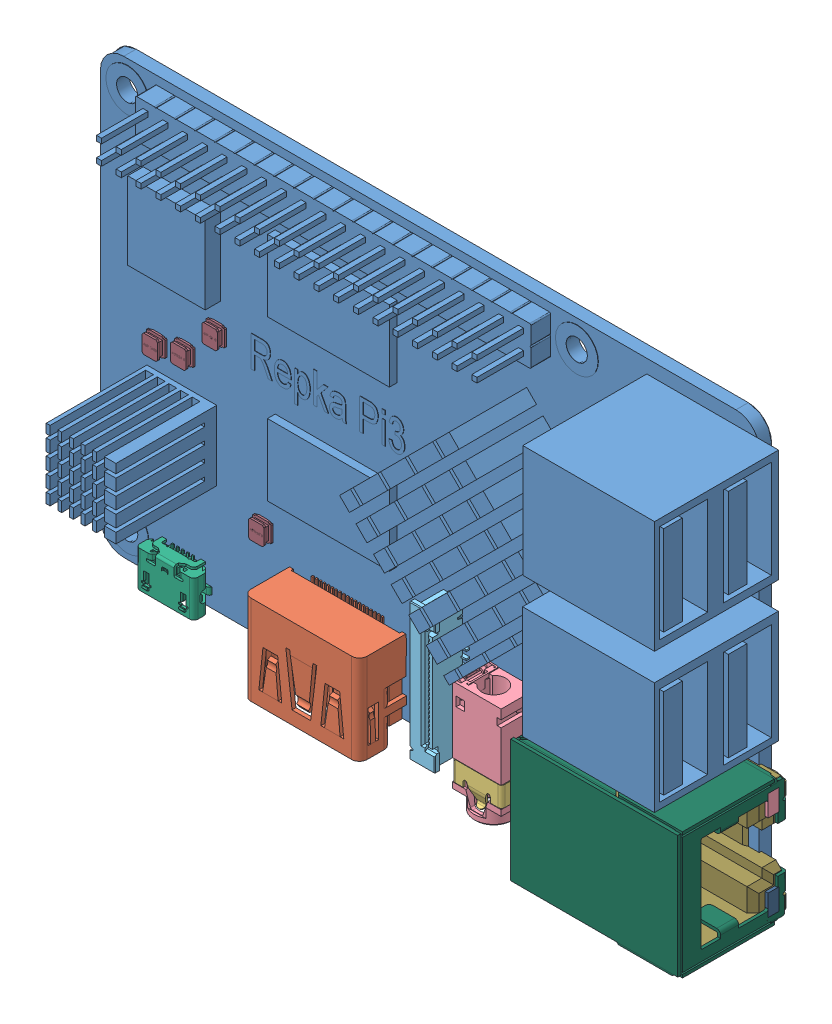
SolidWorks assembly Сборка RepkaPi3, configuration По умолчанию. Lengths in mm.
Overall size (90.06 58 20.41).
57 component instances, 49 part files, 29 mates.
Components (placement in the parent):
- Копия Repka Pi 3 (3D)^Сборка RepkaPi3-1: Копия Repka Pi 3 (3D)^Сборка RepkaPi3 [По умолчанию] at origin size (87.5 56 19.23) (virtual)
- Копия HDMI^Сборка RepkaPi3-1: Копия HDMI^Сборка RepkaPi3 [По умолчанию] at (-5.1944 -35.2371 4.905) x (1 0 0) z (0 -1 0) size (15 7.58 12) (virtual)
- Копия jack3.5_4pin^Сборка RepkaPi3-1: Копия jack3.5_4pin^Сборка RepkaPi3 [По умолчанию] at (-62.0064 -11.1249 -30.918) x (1 0 0) z (0 0 -1) size (8.31 14 5.4) (virtual)
  - Копия CUI_DEVICES_SJ2-35894D-SMT-TR_2^Копия jack3.5_4pin_Сборка RepkaPi3-1: Копия CUI_DEVICES_SJ2-35894D-SMT-TR_2^Копия jack3.5_4pin_Сборка RepkaPi3 [По умолчанию] at origin size (7.35 4.38 4.6) (virtual)
  - Копия CUI_DEVICES_SJ2-35894D-SMT-TR^Копия jack3.5_4pin_Сборка RepkaPi3-1: Копия CUI_DEVICES_SJ2-35894D-SMT-TR^Копия jack3.5_4pin_Сборка RepkaPi3 [По умолчанию] at origin size (8.31 14 5.4) (virtual)
- Копия Шимка^Сборка RepkaPi3-1: Копия Шимка^Сборка RepkaPi3 [По умолчанию] at (8.5556 -24.5871 5.05) x (0 1 0) z (0 0 1) size (17.7 3.8 4.15) (virtual)
- Копия МИКРО ЮСБ^Сборка RepkaPi3-1: Копия МИКРО ЮСБ^Сборка RepkaPi3 [Default] at (-26.4444 -31.2871 2.825) x (1 0 0) z (0 -1 0) size (8.21 3.3 5.5) (virtual)
- Копия ОБРАТНАЯ СТОРОНА^Сборка RepkaPi3-1: Копия ОБРАТНАЯ СТОРОНА^Сборка RepkaPi3 [По умолчанию] at (-28.8944 -3.2371 0) x (0 1 0) z (-1 0 0) size (16.11 2.45 17.8) (virtual)
  - Копия ST-TF-003A_8^Копия ОБРАТНАЯ СТОРОНА_Сборка RepkaPi3-1: Копия ST-TF-003A_8^Копия ОБРАТНАЯ СТОРОНА_Сборка RepkaPi3 [По умолчанию] at origin size (16.11 1.9 14.7) (virtual)
  - Копия ST-TF-003A_3^Копия ОБРАТНАЯ СТОРОНА_Сборка RepkaPi3-1: Копия ST-TF-003A_3^Копия ОБРАТНАЯ СТОРОНА_Сборка RepkaPi3 [По умолчанию] at origin size (1.15 1.16 8.91) (virtual)
  - Копия ST-TF-003A_2^Копия ОБРАТНАЯ СТОРОНА_Сборка RepkaPi3-1: Копия ST-TF-003A_2^Копия ОБРАТНАЯ СТОРОНА_Сборка RepkaPi3 [По умолчанию] at origin size (0.45 0.95 2.68) (virtual)
  - Копия ST-TF-003A^Копия ОБРАТНАЯ СТОРОНА_Сборка RepkaPi3-1: Копия ST-TF-003A^Копия ОБРАТНАЯ СТОРОНА_Сборка RepkaPi3 [По умолчанию] at origin size (0.78 0.5 4.38) (virtual)
  - Копия ST-TF-003A_11^Копия ОБРАТНАЯ СТОРОНА_Сборка RepkaPi3-1: Копия ST-TF-003A_11^Копия ОБРАТНАЯ СТОРОНА_Сборка RepkaPi3 [По умолчанию] at origin size (0.45 1.4 6.44) (virtual)
  - Копия ST-TF-003A_7^Копия ОБРАТНАЯ СТОРОНА_Сборка RepkaPi3-1: Копия ST-TF-003A_7^Копия ОБРАТНАЯ СТОРОНА_Сборка RepkaPi3 [По умолчанию] at origin size (0.45 1.4 6.44) (virtual)
  - Копия ST-TF-003A_10^Копия ОБРАТНАЯ СТОРОНА_Сборка RepkaPi3-1: Копия ST-TF-003A_10^Копия ОБРАТНАЯ СТОРОНА_Сборка RepkaPi3 [По умолчанию] at origin size (0.45 1.4 6.44) (virtual)
  - Копия ST-TF-003A_4^Копия ОБРАТНАЯ СТОРОНА_Сборка RepkaPi3-1: Копия ST-TF-003A_4^Копия ОБРАТНАЯ СТОРОНА_Сборка RepkaPi3 [По умолчанию] at origin size (0.45 1.4 6.44) (virtual)
  - Копия ST-TF-003A_14^Копия ОБРАТНАЯ СТОРОНА_Сборка RepkaPi3-1: Копия ST-TF-003A_14^Копия ОБРАТНАЯ СТОРОНА_Сборка RepkaPi3 [По умолчанию] at origin size (0.45 1.4 6.44) (virtual)
  - Копия ST-TF-003A_12^Копия ОБРАТНАЯ СТОРОНА_Сборка RepkaPi3-1: Копия ST-TF-003A_12^Копия ОБРАТНАЯ СТОРОНА_Сборка RepkaPi3 [По умолчанию] at origin size (0.45 1.4 6.69) (virtual)
  - Копия ST-TF-003A_9^Копия ОБРАТНАЯ СТОРОНА_Сборка RepkaPi3-1: Копия ST-TF-003A_9^Копия ОБРАТНАЯ СТОРОНА_Сборка RepkaPi3 [По умолчанию] at origin size (0.45 1.4 6.69) (virtual)
  - Копия ST-TF-003A_5^Копия ОБРАТНАЯ СТОРОНА_Сборка RepkaPi3-1: Копия ST-TF-003A_5^Копия ОБРАТНАЯ СТОРОНА_Сборка RepkaPi3 [По умолчанию] at origin size (0.45 1.4 6.19) (virtual)
  - Копия ST-TF-003A_13^Копия ОБРАТНАЯ СТОРОНА_Сборка RepkaPi3-1: Копия ST-TF-003A_13^Копия ОБРАТНАЯ СТОРОНА_Сборка RepkaPi3 [По умолчанию] at origin size (2.25 0.95 4.74) (virtual)
  - Копия ST-TF-003A_6^Копия ОБРАТНАЯ СТОРОНА_Сборка RepkaPi3-1: Копия ST-TF-003A_6^Копия ОБРАТНАЯ СТОРОНА_Сборка RepkaPi3 [По умолчанию] at origin size (14.7 2.3 17.3) (virtual)
- Копия HanRun^Сборка RepkaPi3-1: Копия HanRun^Сборка RepkaPi3 [По умолчанию] at (40.0106 -23.3326 1.03) x (0 1 0) z (1 0 0) size (16.33 17.88 21.67) (virtual)
  - Копия SI-61001-F_2^Копия HanRun_Сборка RepkaPi3-1: Копия SI-61001-F_2^Копия HanRun_Сборка RepkaPi3 [По умолчанию] at origin size (1.65 0.65 3.43) (virtual)
  - Копия SI-61001-F_9^Копия HanRun_Сборка RepkaPi3-1: Копия SI-61001-F_9^Копия HanRun_Сборка RepkaPi3 [По умолчанию] at origin size (2.74 1.4 0.38) (virtual)
  - Копия SI-61001-F^Копия HanRun_Сборка RepkaPi3-1: Копия SI-61001-F^Копия HanRun_Сборка RepkaPi3 [По умолчанию] at origin size (0.51 3.26 5.08) (virtual)
  - Копия SI-61001-F_12^Копия HanRun_Сборка RepkaPi3-1: Копия SI-61001-F_12^Копия HanRun_Сборка RepkaPi3 [По умолчанию] at origin size (0.51 3.26 5.08) (virtual)
  - Копия SI-61001-F_19^Копия HanRun_Сборка RepkaPi3-1: Копия SI-61001-F_19^Копия HanRun_Сборка RepkaPi3 [По умолчанию] at origin size (0.51 3.26 5.08) (virtual)
  - Копия SI-61001-F_6^Копия HanRun_Сборка RepkaPi3-1: Копия SI-61001-F_6^Копия HanRun_Сборка RepkaPi3 [По умолчанию] at origin size (0.51 3.26 5.08) (virtual)
  - Копия SI-61001-F_25^Копия HanRun_Сборка RepkaPi3-1: Копия SI-61001-F_25^Копия HanRun_Сборка RepkaPi3 [По умолчанию] at origin size (0.51 3.26 5.08) (virtual)
  - Копия SI-61001-F_18^Копия HanRun_Сборка RepkaPi3-1: Копия SI-61001-F_18^Копия HanRun_Сборка RepkaPi3 [По умолчанию] at origin size (2.74 1.4 0.38) (virtual)
  - Копия SI-61001-F_23^Копия HanRun_Сборка RepkaPi3-1: Копия SI-61001-F_23^Копия HanRun_Сборка RepkaPi3 [По умолчанию] at origin size (0.51 3.26 5.08) (virtual)
  - Копия SI-61001-F_27^Копия HanRun_Сборка RepkaPi3-1: Копия SI-61001-F_27^Копия HanRun_Сборка RepkaPi3 [По умолчанию] at origin size (1.65 0.65 3.43) (virtual)
  - Копия SI-61001-F_21^Копия HanRun_Сборка RepkaPi3-1: Копия SI-61001-F_21^Копия HanRun_Сборка RepkaPi3 [По умолчанию] at origin size (0.51 3.26 5.08) (virtual)
  - Копия SI-61001-F_5^Копия HanRun_Сборка RepkaPi3-1: Копия SI-61001-F_5^Копия HanRun_Сборка RepkaPi3 [По умолчанию] at origin size (0.51 3.26 5.08) (virtual)
  - Копия SI-61001-F_20^Копия HanRun_Сборка RepkaPi3-1: Копия SI-61001-F_20^Копия HanRun_Сборка RepkaPi3 [По умолчанию] at origin size (16.33 17.88 21.67) (virtual)
  - Копия SI-61001-F_16^Копия HanRun_Сборка RepkaPi3-1: Копия SI-61001-F_16^Копия HanRun_Сборка RepkaPi3 [По умолчанию] at origin size (0.57 3.47 0.57) (virtual)
  - Копия SI-61001-F_4^Копия HanRun_Сборка RepkaPi3-1: Копия SI-61001-F_4^Копия HanRun_Сборка RepkaPi3 [По умолчанию] at origin size (0.57 3.47 0.57) (virtual)
  - Копия SI-61001-F_15^Копия HanRun_Сборка RepkaPi3-1: Копия SI-61001-F_15^Копия HanRun_Сборка RepkaPi3 [По умолчанию] at origin size (0.57 3.47 0.57) (virtual)
  - Копия SI-61001-F_10^Копия HanRun_Сборка RepkaPi3-1: Копия SI-61001-F_10^Копия HanRun_Сборка RepkaPi3 [По умолчанию] at origin size (0.57 3.47 0.57) (virtual)
  - Копия SI-61001-F_11^Копия HanRun_Сборка RepkaPi3-1: Копия SI-61001-F_11^Копия HanRun_Сборка RepkaPi3 [По умолчанию] at origin size (0.57 3.47 0.57) (virtual)
  - Копия SI-61001-F_8^Копия HanRun_Сборка RepkaPi3-1: Копия SI-61001-F_8^Копия HanRun_Сборка RepkaPi3 [По умолчанию] at origin size (0.57 3.47 0.57) (virtual)
  - Копия SI-61001-F_22^Копия HanRun_Сборка RepkaPi3-1: Копия SI-61001-F_22^Копия HanRun_Сборка RepkaPi3 [По умолчанию] at origin size (0.57 3.47 0.57) (virtual)
  - Копия SI-61001-F_3^Копия HanRun_Сборка RepkaPi3-1: Копия SI-61001-F_3^Копия HanRun_Сборка RepkaPi3 [По умолчанию] at origin size (0.57 3.47 0.57) (virtual)
  - Копия SI-61001-F_14^Копия HanRun_Сборка RepkaPi3-1: Копия SI-61001-F_14^Копия HanRun_Сборка RepkaPi3 [По умолчанию] at origin size (0.57 3.47 0.57) (virtual)
  - Копия SI-61001-F_26^Копия HanRun_Сборка RepkaPi3-1: Копия SI-61001-F_26^Копия HanRun_Сборка RepkaPi3 [По умолчанию] at origin size (0.57 3.47 0.57) (virtual)
  - Копия SI-61001-F_13^Копия HanRun_Сборка RepkaPi3-1: Копия SI-61001-F_13^Копия HanRun_Сборка RepkaPi3 [По умолчанию] at origin size (0.57 3.47 0.57) (virtual)
  - Копия SI-61001-F_28^Копия HanRun_Сборка RepkaPi3-1: Копия SI-61001-F_28^Копия HanRun_Сборка RepkaPi3 [По умолчанию] at origin size (0.57 3.47 0.57) (virtual)
  - Копия SI-61001-F_17^Копия HanRun_Сборка RepkaPi3-1: Копия SI-61001-F_17^Копия HanRun_Сборка RepkaPi3 [По умолчанию] at origin size (0.57 3.47 0.57) (virtual)
  - Копия SI-61001-F_24^Копия HanRun_Сборка RepkaPi3-1: Копия SI-61001-F_24^Копия HanRun_Сборка RepkaPi3 [По умолчанию] at origin size (0.57 3.47 0.57) (virtual)
  - Копия SI-61001-F_7^Копия HanRun_Сборка RepkaPi3-1: Копия SI-61001-F_7^Копия HanRun_Сборка RepkaPi3 [По умолчанию] at origin size (15.37 16.76 20.83) (virtual)
- Копия IND-2410^Сборка RepkaPi3-1: Копия IND-2410^Сборка RepkaPi3 [По умолчанию] at (-34.4944 -16.2371 1.6) x (1 0 0) z (0 -1 0) size (2.4 1.01 2.4) (virtual)
- Копия IND-2410^Сборка RepkaPi3-2: Копия IND-2410^Сборка RepkaPi3 [По умолчанию] at (-29.9944 -24.6371 1.6) x (1 0 0) z (0 -1 0) size (2.4 1.01 2.4) (virtual)
- Копия IND-2410^Сборка RepkaPi3-3: Копия IND-2410^Сборка RepkaPi3 [По умолчанию] at (-22.1193 -2.2293 1.6) x (1 0 0) z (0 -1 0) size (2.4 1.01 2.4) (virtual)
- Копия IND-2410^Сборка RepkaPi3-4: Копия IND-2410^Сборка RepkaPi3 [По умолчанию] at (-29.8223 -7.2768 1.6) x (1 0 0) z (0 -1 0) size (2.4 1.01 2.4) (virtual)
- Копия IND-2410^Сборка RepkaPi3-5: Копия IND-2410^Сборка RepkaPi3 [По умолчанию] at (-26.1713 -6.4508 1.6) x (1 0 0) z (0 -1 0) size (2.4 1.01 2.4) (virtual)
- Копия IND-2410^Сборка RepkaPi3-6: Копия IND-2410^Сборка RepkaPi3 [По умолчанию] at (-16.1087 -21.1116 1.6) x (1 0 0) z (0 -1 0) size (2.4 1.01 2.4) (virtual)
Mates (geometry in assembly coordinates):
- Совпадение3: coincident aligned: plane of Копия Repka Pi 3 (3D)^Сборка RepkaPi3-1 through (0 -33.4371 1.6) normal (0 -1 0); plane of Копия HDMI^Сборка RepkaPi3-1 through (-5.1944 -33.4371 4.905) normal (0 -1 0)
- Расстояние1: distance = 24.5 mm aligned: plane of Копия HDMI^Сборка RepkaPi3-1 through (-12.6944 -35.2371 6.68) normal (-1 0 0); plane of Копия Repka Pi 3 (3D)^Сборка RepkaPi3-1 through (-37.1944 0 1.6) normal (-1 0 0)
- Совпадение5: coincident anti-aligned: plane of Копия Repka Pi 3 (3D)^Сборка RepkaPi3-1 through (0 0 1.6) normal (0 0 1); plane of Копия jack3.5_4pin^Сборка RepkaPi3-1/Копия CUI_DEVICES_SJ2-35894D-SMT-TR^Копия jack3.5_4pin_Сборка RepkaPi3-1 through (13.6056 -31.8371 1.6) normal (0 0 -1)
- Совпадение6: coincident aligned: plane of Копия Repka Pi 3 (3D)^Сборка RepkaPi3-1 through (0 -33.4371 1.6) normal (0 -1 0); plane of Копия jack3.5_4pin^Сборка RepkaPi3-1/Копия CUI_DEVICES_SJ2-35894D-SMT-TR^Копия jack3.5_4pin_Сборка RepkaPi3-1 through (19.1056 -33.4371 1.7) normal (0 -1 0)
- Расстояние2: distance = 50 mm aligned: plane of Копия jack3.5_4pin^Сборка RepkaPi3-1/Копия CUI_DEVICES_SJ2-35894D-SMT-TR^Копия jack3.5_4pin_Сборка RepkaPi3-1 through (12.8056 -21.5038 5.6967) normal (-1 0 0); plane of Копия Repka Pi 3 (3D)^Сборка RepkaPi3-1 through (-37.1944 0 1.6) normal (-1 0 0)
- Совпадение8: coincident anti-aligned: plane of Копия Repka Pi 3 (3D)^Сборка RepkaPi3-1 through (0 0 1.6) normal (0 0 1); plane of Копия Шимка^Сборка RepkaPi3-1 through (10.4556 -30.4371 1.6) normal (0 0 -1)
- Совпадение9: coincident aligned: plane of Копия Repka Pi 3 (3D)^Сборка RepkaPi3-1 through (0 -33.4371 1.6) normal (0 -1 0); plane of Копия Шимка^Сборка RepkaPi3-1 through (6.8056 -33.4371 5.75) normal (0 -1 0)
- Расстояние3: distance = 44 mm aligned: plane of Копия Шимка^Сборка RepkaPi3-1 through (6.8056 -32.4461 5.75) normal (-1 0 0); plane of Копия Repka Pi 3 (3D)^Сборка RepkaPi3-1 through (-37.1944 0 1.6) normal (-1 0 0)
- Совпадение12: coincident: plane of Копия Repka Pi 3 (3D)^Сборка RepkaPi3-1 through (0 0 1.6) normal (0 0 1); line of Копия МИКРО ЮСБ^Сборка RepkaPi3-1 through (-29.5194 -31.8221 1.6) axis (0 1 0)
- Расстояние4: distance = 0.2 mm aligned: plane of Копия МИКРО ЮСБ^Сборка RepkaPi3-1 through (-26.4444 -33.6371 2.825) normal (0 -1 0); plane of Копия Repka Pi 3 (3D)^Сборка RepkaPi3-1 through (0 -33.4371 1.6) normal (0 -1 0)
- Расстояние5: distance = 7 mm aligned: plane of Копия МИКРО ЮСБ^Сборка RepkaPi3-1 through (-30.1944 -28.9371 3.5) normal (-1 0 0); plane of Копия Repka Pi 3 (3D)^Сборка RepkaPi3-1 through (-37.1944 0 1.6) normal (-1 0 0)
- Совпадение15: coincident anti-aligned: plane of Копия Repka Pi 3 (3D)^Сборка RepkaPi3-1 through (0 0 0) normal (0 0 -1); plane of Копия ОБРАТНАЯ СТОРОНА^Сборка RepkaPi3-1/Копия ST-TF-003A_8^Копия ОБРАТНАЯ СТОРОНА_Сборка RepkaPi3-1 through (-28.8944 -3.2371 0) normal (0 0 1)
- Расстояние6: distance = 0.8 mm aligned: plane of Копия ОБРАТНАЯ СТОРОНА^Сборка RepkaPi3-1/Копия ST-TF-003A_6^Копия ОБРАТНАЯ СТОРОНА_Сборка RepkaPi3-1 through (-36.3944 -3.2371 -0.8) normal (-1 0 0); plane of Копия Repka Pi 3 (3D)^Сборка RepkaPi3-1 through (-37.1944 0 1.6) normal (-1 0 0)
- Расстояние7: distance = 18.45 mm aligned: plane of Копия ОБРАТНАЯ СТОРОНА^Сборка RepkaPi3-1/Копия ST-TF-003A_8^Копия ОБРАТНАЯ СТОРОНА_Сборка RepkaPi3-1 through (-28.8944 4.1129 0) normal (0 1 0); plane of Копия Repka Pi 3 (3D)^Сборка RepkaPi3-1 through (0 22.5629 1.6) normal (0 1 0)
- Совпадение18: coincident anti-aligned: plane of Копия Repka Pi 3 (3D)^Сборка RepkaPi3-1 through (0 0 1.6) normal (0 0 1); plane of Копия HDMI^Сборка RepkaPi3-1 through (-9.8094 -24.3371 1.6) normal (0 0 -1)
- Расстояние8: distance = 3 mm aligned: plane of Копия HanRun^Сборка RepkaPi3-1/Копия SI-61001-F_20^Копия HanRun_Сборка RepkaPi3-1 through (50.8056 -23.3326 1.03) normal (1 0 0); plane of Копия Repka Pi 3 (3D)^Сборка RepkaPi3-1 through (47.8056 0 1.6) normal (1 0 0)
- Совпадение21: coincident anti-aligned: plane of Копия Repka Pi 3 (3D)^Сборка RepkaPi3-1 through (0 0 1.6) normal (0 0 1); plane of Копия IND-2410^Сборка RepkaPi3-1 through (-34.4944 -16.2371 1.6) normal (0 0 -1)
- Совпадение22: coincident anti-aligned: plane of Копия Repka Pi 3 (3D)^Сборка RepkaPi3-1 through (0 0 1.6) normal (0 0 1); plane of Копия IND-2410^Сборка RepkaPi3-2 through (-29.9944 -24.6371 1.6) normal (0 0 -1)
- Расстояние10: distance = 1.5 mm aligned: plane of Копия IND-2410^Сборка RepkaPi3-1 through (-35.6944 -15.0371 1.85) normal (-1 0 0); plane of Копия Repka Pi 3 (3D)^Сборка RepkaPi3-1 through (-37.1944 0 1.6) normal (-1 0 0)
- Расстояние12: distance = 2 mm aligned: plane of Копия Repka Pi 3 (3D)^Сборка RepkaPi3-1 through (-31.1944 -19.4371 14.6) normal (0 -1 0); plane of Копия IND-2410^Сборка RepkaPi3-1 through (-35.6944 -17.4371 1.85) normal (0 -1 0)
- Расстояние13: distance = 6 mm aligned: plane of Копия IND-2410^Сборка RepkaPi3-2 through (-31.1944 -23.4371 1.85) normal (-1 0 0); plane of Копия Repka Pi 3 (3D)^Сборка RepkaPi3-1 through (-37.1944 0 1.6) normal (-1 0 0)
- Расстояние14: distance = 4 mm anti-aligned: plane of Копия Repka Pi 3 (3D)^Сборка RepkaPi3-1 through (-31.1944 -19.4371 14.6) normal (0 -1 0); plane of Копия IND-2410^Сборка RepkaPi3-2 through (-31.1944 -23.4371 1.85) normal (0 1 0)
- Совпадение28: coincident anti-aligned: plane of Копия Repka Pi 3 (3D)^Сборка RepkaPi3-1 through (0 0 1.6) normal (0 0 1); plane of Копия IND-2410^Сборка RepkaPi3-4 through (-29.8223 -7.2768 1.6) normal (0 0 -1)
- Совпадение29: coincident anti-aligned: plane of Копия Repka Pi 3 (3D)^Сборка RepkaPi3-1 through (0 0 1.6) normal (0 0 1); plane of Копия IND-2410^Сборка RepkaPi3-5 through (-26.1713 -6.4508 1.6) normal (0 0 -1)
- Совпадение30: coincident anti-aligned: plane of Копия Repka Pi 3 (3D)^Сборка RepkaPi3-1 through (0 0 1.6) normal (0 0 1); plane of Копия IND-2410^Сборка RepkaPi3-6 through (-16.1087 -21.1116 1.6) normal (0 0 -1)
- Совпадение31: coincident anti-aligned: plane of Копия Repka Pi 3 (3D)^Сборка RepkaPi3-1 through (0 0 1.6) normal (0 0 1); plane of Копия IND-2410^Сборка RepkaPi3-3 through (-22.1193 -2.2293 1.6) normal (0 0 -1)
- Расстояние15: distance = 2.5 mm anti-aligned: plane of Копия Repka Pi 3 (3D)^Сборка RepkaPi3-1 through (-31.672 1.4707 3.6) normal (0 -1 0); plane of Копия IND-2410^Сборка RepkaPi3-3 through (-23.3193 -1.0293 1.85) normal (0 1 0)
- Расстояние16: distance = 13.5 mm aligned: plane of Копия Repka Pi 3 (3D)^Сборка RepkaPi3-1 through (0 0 1.6) normal (0 0 1); plane of Копия HanRun^Сборка RepkaPi3-1/Копия SI-61001-F_20^Копия HanRun_Сборка RepkaPi3-1 through (40.0106 -23.3326 15.1) normal (0 0 1)
- Расстояние17: distance = 1.94 mm aligned: plane of Копия HanRun^Сборка RepkaPi3-1/Копия SI-61001-F_20^Копия HanRun_Сборка RepkaPi3-1 through (40.0106 -31.4971 1.03) normal (0 -1 0); plane of Копия Repka Pi 3 (3D)^Сборка RepkaPi3-1 through (0 -33.4371 1.6) normal (0 -1 0)
